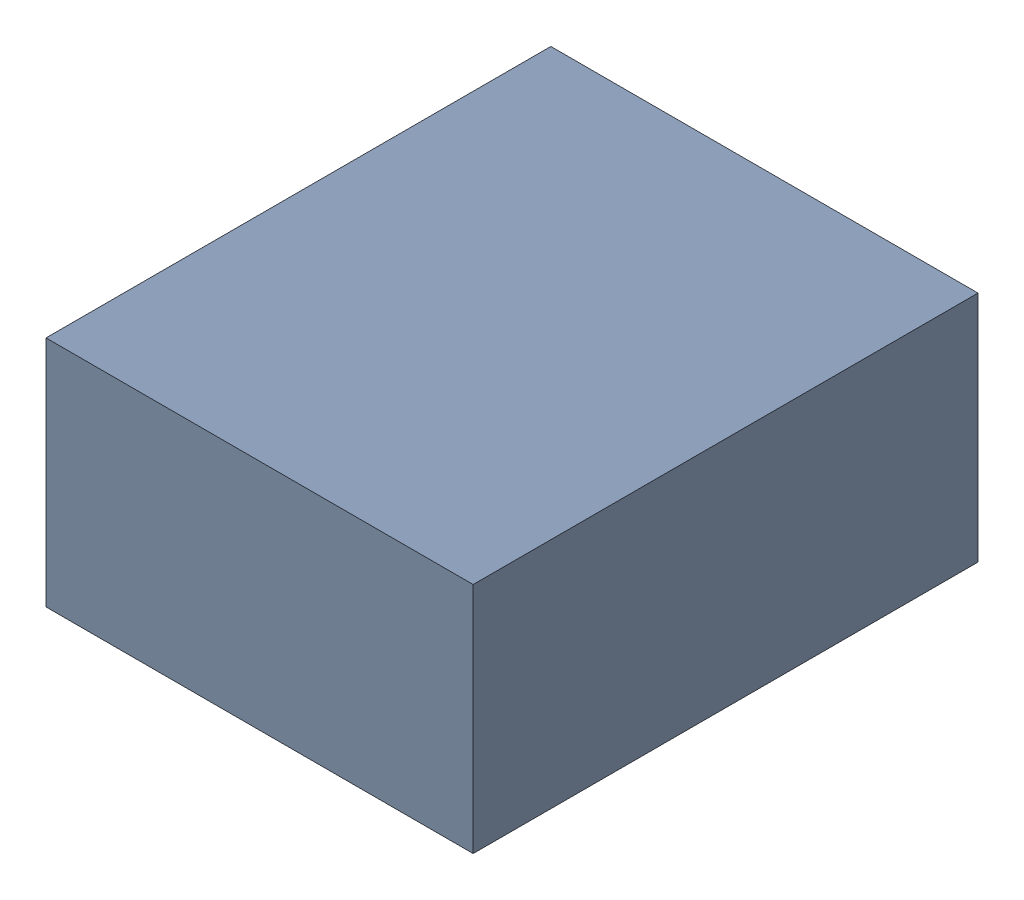
SolidWorks assembly C206, configuration Standard. Lengths in mm.
Overall size (1.1 0.6 1.3).
2 component instances, 1 part files, 0 mates.
Components (placement in the parent):
- 885542240-1: 885542240 [Standard] at (15.1 -13.495 0) size (1.1 0.6 1.3)
  - Extruded_28-1: Extruded_28 [Standard] at origin size (1.1 0.6 1.3)
